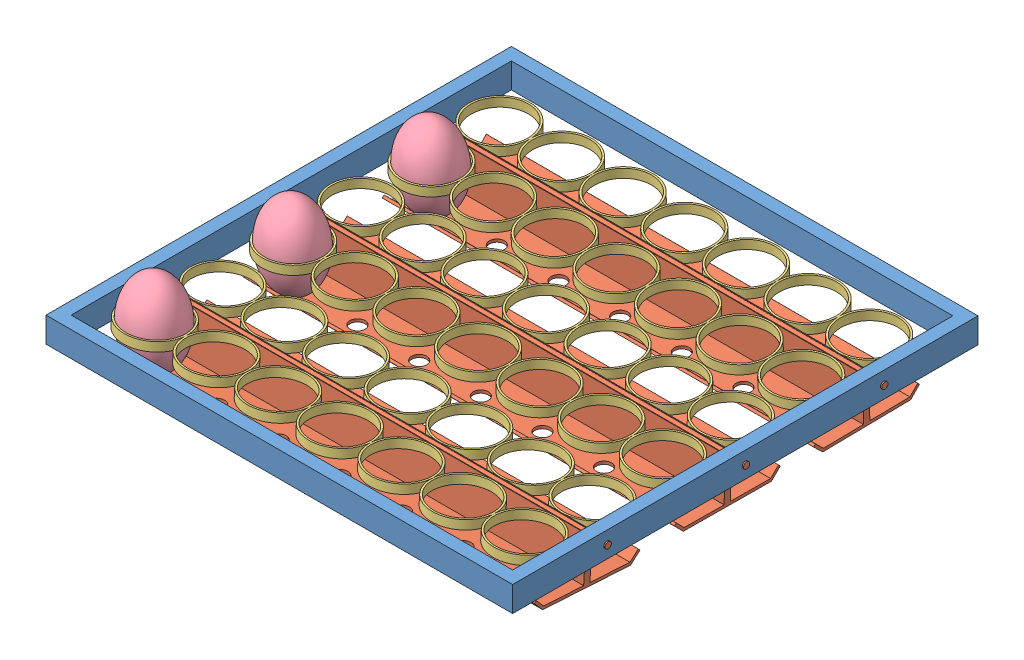
SolidWorks assembly lapghepkhungmoi, configuration Default. Lengths in mm.
Overall size (373 77.95 370).
58 component instances, 4 part files, 6 mates.
Components (placement in the parent):
- khungmoi-1: khungmoi [Default] at (109.0165 201.6836 352.6796) size (371 20 370)
- lapghep1danmoi-1: lapghep1danmoi [Default] at (-39.5629 -27.6709 -95.9092) x (1 0 0) z (0 -0.01448 0.999895) size (373 71.36 109.63)
  - trucchinhmoi-1: trucchinhmoi [Default] at (148.5794 210.732 335.0874) size (373 38 84.14)
  - lapghepmoi-1: lapghepmoi [Default] at (199.6763 214.875 314.9312) size (343 7 49)
    - 1oluoi-1: 1oluoi [Default] at (-2.097 23.8571 47.1563) size (49 7 49)
    - 1oluoi-2: 1oluoi [Default] at (46.903 23.8571 47.1563) size (49 7 49)
    - 1oluoi-3: 1oluoi [Default] at (-51.097 23.8571 47.1563) size (49 7 49)
    - 1oluoi-4: 1oluoi [Default] at (-100.097 23.8571 47.1563) size (49 7 49)
    - 1oluoi-5: 1oluoi [Default] at (95.903 23.8571 47.1563) size (49 7 49)
    - 1oluoi-6: 1oluoi [Default] at (-149.097 23.8571 47.1563) size (49 7 49)
    - 1oluoi-7: 1oluoi [Default] at (-198.097 23.8571 47.1563) size (49 7 49)
  - lapghepmoi-2: lapghepmoi [Default] at (199.6763 214.875 260.9312) size (343 7 49)
    - 1oluoi-1: 1oluoi [Default] at (-2.097 23.8571 47.1563) size (49 7 49)
    - 1oluoi-2: 1oluoi [Default] at (46.903 23.8571 47.1563) size (49 7 49)
    - 1oluoi-3: 1oluoi [Default] at (-51.097 23.8571 47.1563) size (49 7 49)
    - 1oluoi-4: 1oluoi [Default] at (-100.097 23.8571 47.1563) size (49 7 49)
    - 1oluoi-5: 1oluoi [Default] at (95.903 23.8571 47.1563) size (49 7 49)
    - 1oluoi-6: 1oluoi [Default] at (-149.097 23.8571 47.1563) size (49 7 49)
    - 1oluoi-7: 1oluoi [Default] at (-198.097 23.8571 47.1563) size (49 7 49)
  - trungga-1: trungga [Default] at (1.586 243.3071 362.5857) x (-0.880436 -0.105529 0.462274) z (-0.46012 -0.045387 -0.886696) size (45 65 45)
- lapghep1danmoi-2: lapghep1danmoi [Default] at (-39.5629 -35.4489 19.7255) x (1 0 0) z (0 0.008683 0.999962) size (373 71.36 109.63)
  - trucchinhmoi-1: trucchinhmoi [Default] at (148.5794 210.732 335.0874) size (373 38 84.14)
  - lapghepmoi-1: lapghepmoi [Default] at (199.6763 214.875 314.9312) size (343 7 49)
    - 1oluoi-1: 1oluoi [Default] at (-2.097 23.8571 47.1563) size (49 7 49)
    - 1oluoi-2: 1oluoi [Default] at (46.903 23.8571 47.1563) size (49 7 49)
    - 1oluoi-3: 1oluoi [Default] at (-51.097 23.8571 47.1563) size (49 7 49)
    - 1oluoi-4: 1oluoi [Default] at (-100.097 23.8571 47.1563) size (49 7 49)
    - 1oluoi-5: 1oluoi [Default] at (95.903 23.8571 47.1563) size (49 7 49)
    - 1oluoi-6: 1oluoi [Default] at (-149.097 23.8571 47.1563) size (49 7 49)
    - 1oluoi-7: 1oluoi [Default] at (-198.097 23.8571 47.1563) size (49 7 49)
  - lapghepmoi-2: lapghepmoi [Default] at (199.6763 214.875 260.9312) size (343 7 49)
    - 1oluoi-1: 1oluoi [Default] at (-2.097 23.8571 47.1563) size (49 7 49)
    - 1oluoi-2: 1oluoi [Default] at (46.903 23.8571 47.1563) size (49 7 49)
    - 1oluoi-3: 1oluoi [Default] at (-51.097 23.8571 47.1563) size (49 7 49)
    - 1oluoi-4: 1oluoi [Default] at (-100.097 23.8571 47.1563) size (49 7 49)
    - 1oluoi-5: 1oluoi [Default] at (95.903 23.8571 47.1563) size (49 7 49)
    - 1oluoi-6: 1oluoi [Default] at (-149.097 23.8571 47.1563) size (49 7 49)
    - 1oluoi-7: 1oluoi [Default] at (-198.097 23.8571 47.1563) size (49 7 49)
  - trungga-1: trungga [Default] at (1.586 243.3071 362.5857) x (-0.880436 -0.105529 0.462274) z (-0.46012 -0.045387 -0.886696) size (45 65 45)
- lapghep1danmoi-3: lapghep1danmoi [Default] at (-39.5629 -52.6464 143.2073) x (1 0 0) z (0 0.061351 0.998116) size (373 71.36 109.63)
  - trucchinhmoi-1: trucchinhmoi [Default] at (148.5794 210.732 335.0874) size (373 38 84.14)
  - lapghepmoi-1: lapghepmoi [Default] at (199.6763 214.875 314.9312) size (343 7 49)
    - 1oluoi-1: 1oluoi [Default] at (-2.097 23.8571 47.1563) size (49 7 49)
    - 1oluoi-2: 1oluoi [Default] at (46.903 23.8571 47.1563) size (49 7 49)
    - 1oluoi-3: 1oluoi [Default] at (-51.097 23.8571 47.1563) size (49 7 49)
    - 1oluoi-4: 1oluoi [Default] at (-100.097 23.8571 47.1563) size (49 7 49)
    - 1oluoi-5: 1oluoi [Default] at (95.903 23.8571 47.1563) size (49 7 49)
    - 1oluoi-6: 1oluoi [Default] at (-149.097 23.8571 47.1563) size (49 7 49)
    - 1oluoi-7: 1oluoi [Default] at (-198.097 23.8571 47.1563) size (49 7 49)
  - lapghepmoi-2: lapghepmoi [Default] at (199.6763 214.875 260.9312) size (343 7 49)
    - 1oluoi-1: 1oluoi [Default] at (-2.097 23.8571 47.1563) size (49 7 49)
    - 1oluoi-2: 1oluoi [Default] at (46.903 23.8571 47.1563) size (49 7 49)
    - 1oluoi-3: 1oluoi [Default] at (-51.097 23.8571 47.1563) size (49 7 49)
    - 1oluoi-4: 1oluoi [Default] at (-100.097 23.8571 47.1563) size (49 7 49)
    - 1oluoi-5: 1oluoi [Default] at (95.903 23.8571 47.1563) size (49 7 49)
    - 1oluoi-6: 1oluoi [Default] at (-149.097 23.8571 47.1563) size (49 7 49)
    - 1oluoi-7: 1oluoi [Default] at (-198.097 23.8571 47.1563) size (49 7 49)
  - trungga-1: trungga [Default] at (1.586 243.3071 362.5857) x (-0.880436 -0.105529 0.462274) z (-0.46012 -0.045387 -0.886696) size (45 65 45)
Mates (geometry in assembly coordinates):
- Distance1: distance = 4 mm anti-aligned: plane of lapghep1danmoi-1/trucchinhmoi-1 through (280.5165 213.1472 245.201) normal (1 0 0); plane of khungmoi-1 through (284.5165 221.6836 527.6796) normal (-1 0 0)
- Distance2: distance = 4 mm anti-aligned: plane of khungmoi-1 through (284.5165 221.6836 527.6796) normal (-1 0 0); plane of lapghep1danmoi-2/trucchinhmoi-1 through (280.5165 213.2052 355.1665) normal (1 0 0)
- Distance3: distance = 4 mm: plane of khungmoi-1 through (284.5165 221.6836 527.6796) normal (-1 0 0); plane of lapghep1danmoi-3/trucchinhmoi-1 through (280.5165 213.3341 465.0828) normal (1 0 0)
- Coincident1: coincident: circle of khungmoi-1; cylinder of lapghep1danmoi-2/trucchinhmoi-1 through (295.5165 211.6836 352.6796) axis (-1 0 0) radius 2.5
- Concentric3: concentric: cylinder of khungmoi-1 through (-83.5546 211.6836 462.6796) axis (1 0 0) radius 2.5; cylinder of lapghep1danmoi-3/trucchinhmoi-1 through (295.5165 211.6836 462.6796) axis (-1 0 0) radius 2.5
- Concentric4: concentric anti-aligned: cylinder of khungmoi-1 through (-83.5546 211.6836 242.6796) axis (1 0 0) radius 2.5; cylinder of lapghep1danmoi-1/trucchinhmoi-1 through (295.5165 211.6836 242.6796) axis (-1 0 0) radius 2.5
